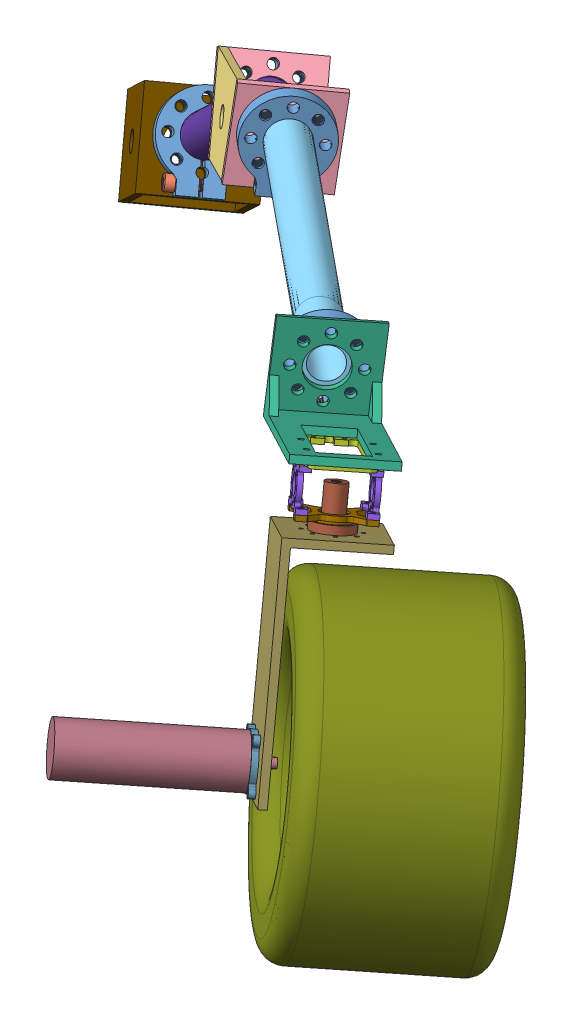
SolidWorks assembly ROVER_ASSM, configuration Default. Lengths in mm.
Overall size (756.93 575.28 702.78).
39 component instances, 18 part files, 23 mates.
Components (placement in the parent):
- Clamping hub 1inch-1: Clamping hub 1inch [Default] at (-73.9561 214.0923 1402.8764) x (0.66198 -0.147614 -0.734841) z (-0.023433 0.975859 -0.217139) size (50.8 9.91 57.17)
  - 545356-1: 545356 [Default] at (-68.793 17.8362 24.1343) size (50.8 9.91 57.17)
  - 91251A542_91251A542-1: 91251A542_91251A542 [Default] at (-81.493 22.5987 -1.2123) x (0 0 1) z (-1 0 0) size (9.53 9.53 32.08)
- Middle_hub_subassem-1: Middle_hub_subassem [Default] at (-169.6755 232.0509 1518.4362) x (-0.717563 -0.408048 -0.564447) z (0.66198 -0.147614 -0.734841) size (96.06 567.55 57.15)
  - center_middle_hub-1: center_middle_hub [Default] at (63.6023 29.7357 53.5654) size (86.73 567.55 4.83)
  - Left_right_middle_hub-1: Left_right_middle_hub [Default] at (26.6634 27.2017 62.7035) x (0.965926 0.258819 0) z (0 0 1) size (4.83 57.15 57.15)
  - Left_right_middle_hub-2: Left_right_middle_hub [Default] at (99.6896 28.4508 62.7035) x (0.965926 -0.258819 0) z (0 0 1) size (4.83 57.15 57.15)
- 1OD tubing bent-2: 1OD tubing bent [Default<As Machined>] at (-21.8827 243.4944 1537.4966) x (-0.749155 -0.160962 -0.642541) z (0.66198 -0.147614 -0.734841) size (269.75 179.7 25.4)
- Clamping hub 1inch-6: Clamping hub 1inch [Default] at (117.7515 256.9533 1566.1024) x (0.661092 -0.120859 -0.740507) z (-0.041537 0.979533 -0.196952) size (50.8 9.91 57.17)
  - 545356-1: 545356 [Default] at (-68.793 17.8362 24.1343) size (50.8 9.91 57.17)
  - 91251A542_91251A542-1: 91251A542_91251A542 [Default] at (-81.493 22.5987 -1.2123) x (0 0 1) z (-1 0 0) size (9.53 9.53 32.08)
- Front_wheel_SUBASSEM-1: Front_wheel_SUBASSEM [Default] at (124.6017 279.882 1760.4193) x (-0.712877 -0.408999 -0.569672) z (0.661092 -0.120859 -0.740507) size (203.2 315.88 229.31)
  - Servo_base_front-1: Servo_base_front [Default] at (66.9376 47.4067 44.7676) size (127 55.2 57.15)
  - servo_mount-1: servo_mount [Default] at (63.4948 44.2317 73.3426) size (79.25 3.17 42.93)
  - wheel_hold_left_right-1: wheel_hold_left_right [Default] at (47.8121 31.5317 51.8796) x (0 -1 0) z (-1 0 0) size (25.4 6.35 33.02)
  - wheel_hold_left_right-2: wheel_hold_left_right [Default] at (47.8121 31.5317 94.8056) x (0 1 0) z (-1 0 0) size (25.4 6.35 33.02)
  - Bearing_mount_subsubass-1: Bearing_mount_subsubass [Default] at (82.6306 37.2877 87.6325) x (0 0 -1) z (-1 0 0) size (42.93 5.08 33.27)
    - 535182-1: 535182 [Default] at (14.2899 18.456 34.8186) size (42.93 5.08 33.27)
    - .5 x .75 non flanged bearing-1: .5 x .75 non flanged bearing [Default] at (14.2899 19.5736 34.8186) x (0.770155 0 0.637857) z (-0.637857 0 0.770155) size (19.05 3.91 19.05)
  - Mounting_hub_circular_servo-1: Mounting_hub_circular_servo [Default] at (47.8121 8.9765 73.3426) x (-0.707107 0 -0.707107) z (0.707107 0 -0.707107) size (25.39 25.4 25.39)
  - Wheel_extension_sheet-2: Wheel_extension_sheet [Default] at (19.2371 8.9765 101.9176) size (57.15 139.7 57.15)
  - Motor_and_mount_subass-1: Motor_and_mount_subass [Default] at (28.0226 -206.4882 -27.8911) x (0.696282 0.717769 0) z (0 0 1) size (46.7 46.7 115)
    - Motors-1: Motors [Default] at (81.834 51.8135 -31.3435) size (32 32 115)
    - Motor_mount-2: Motor_mount [Default] at (45.268 5.1287 35.3702) x (-0.707107 -0.707107 0) z (-0.707107 0.707107 0) size (33.02 8.74 33.02)
      - 555174-1: 555174 [Default] at (-58.8675 33.2863 7.1552) size (33.02 4.05 33.02)
      - 555174 screw_92005A116-1: 555174 screw_92005A116 [Default] at (-68.0596 28.5563 -2.0369) x (1 0 0) z (0 1 0) size (6 6 8.48)
      - 555174 screw_92005A116-2: 555174 screw_92005A116 [Default] at (-68.0596 28.5563 16.3474) x (0 0 -1) z (0 1 0) size (6 6 8.48)
      - 555174 screw_92005A116-3: 555174 screw_92005A116 [Default] at (-49.6753 28.5563 16.3474) x (-1 0 0) z (0 1 0) size (6 6 8.48)
      - 555174 screw_92005A116-4: 555174 screw_92005A116 [Default] at (-49.6753 28.5563 -2.0369) x (0 0 1) z (0 1 0) size (6 6 8.48)
  - wheel_exa_1-1: wheel_exa_1 [Default] at (47.8121 -111.6735 55.7793) size (203.2 203.2 116.84)
- subassem_rightlink-1: subassem_rightlink [Default] at (-260.8229 137.638 1643.4581) x (-0.63707 -0.627327 -0.447887) z (0.66198 -0.147614 -0.734841) size (312.87 60.57 63.5)
  - tubing1rl-1: tubing1rl [Default<As Machined>] at (32.4558 163.244 220.4128) size (254 25.4 25.4)
  - Clamping hub 1inch-1: Clamping hub 1inch [Default] at (14.6195 139.1097 289.2058) x (0 0 1) z (0 1 0) size (50.8 9.91 57.17)
    - 545356-1: 545356 [Default] at (-68.793 17.8362 24.1343) size (50.8 9.91 57.17)
    - 91251A542_91251A542-1: 91251A542_91251A542 [Default] at (-81.493 22.5987 -1.2123) x (0 0 1) z (-1 0 0) size (9.53 9.53 32.08)
  - Clamping hub 1inch-2: Clamping hub 1inch [Default] at (299.466 139.1097 151.6198) x (0 0 -1) z (0 1 0) size (50.8 9.91 57.17)
    - 545356-1: 545356 [Default] at (-68.793 17.8362 24.1343) size (50.8 9.91 57.17)
    - 91251A542_91251A542-1: 91251A542_91251A542 [Default] at (-81.493 22.5987 -1.2123) x (0 0 1) z (-1 0 0) size (9.53 9.53 32.08)
  - right_block-1: right_block [Default] at (345.1298 163.244 220.4128) x (0 0 1) z (-1 0 0) size (63.5 57.15 63.5)
Mates (geometry in assembly coordinates):
- Concentric1: concentric anti-aligned: cylinder of ? through (329.3554 390.3641 930.5142) axis (0 0 -1) radius 12.7; cylinder of Clamping hub 1inch-1/545356-1 through (329.3554 390.3641 182.4842) axis (0 0 1) radius 12.7
- Coincident1: coincident aligned: plane of ? through (329.3554 390.3641 177.6582) normal (0 0 -1); plane of Middle_hub_subassem-1/Left_right_middle_hub-1
- Coincident3: coincident anti-aligned: plane of Clamping hub 1inch-1/545356-1 through (-140.5591 243.3947 1430.6072) normal (-0.749155 -0.160962 -0.642541); plane of Middle_hub_subassem-1/Left_right_middle_hub-1 through (-153.1896 236.4223 1447.08) normal (0.749155 0.160962 0.642541)
- Concentric3: concentric anti-aligned: cylinder of Clamping hub 1inch-1/545356-1 through (-141.0055 261.9848 1426.4707) axis (-0.749155 -0.160962 -0.642541) radius 3.175; cylinder of Middle_hub_subassem-1/Left_right_middle_hub-1 through (-144.6209 261.208 1423.3698) axis (0.749155 0.160962 0.642541) radius 3.175
- Coincident4: coincident anti-aligned: plane of Clamping hub 1inch-1/545356-1 through (-140.5591 243.3947 1430.6072) normal (-0.749155 -0.160962 -0.642541); plane of Middle_hub_subassem-1/Left_right_middle_hub-1 through (-153.1896 236.4223 1447.08) normal (0.749155 0.160962 0.642541)
- Concentric4: concentric anti-aligned: cylinder of Clamping hub 1inch-1/545356-1 through (-141.0055 261.9848 1426.4707) axis (-0.749155 -0.160962 -0.642541) radius 3.175; cylinder of Middle_hub_subassem-1/Left_right_middle_hub-1 through (-144.6209 261.208 1423.3698) axis (0.749155 0.160962 0.642541) radius 3.175
- Concentric5: concentric anti-aligned: cylinder of Clamping hub 1inch-1/545356-1 through (-127.9484 240.5826 1416.6084) axis (-0.749155 -0.160962 -0.642541) radius 3.175; cylinder of Middle_hub_subassem-1/Left_right_middle_hub-1 through (-131.5638 239.8058 1413.5075) axis (0.749155 0.160962 0.642541) radius 3.175
- Parallel13: parallel aligned: line of Middle_hub_subassem-1/Left_right_middle_hub-1 through (-141.1543 268.1815 1425.0918) axis (0.023433 -0.975859 0.217139); line of 1OD tubing bent-2 through (-144.4721 255.0113 1424.7486) axis (0.023433 -0.975859 0.217139)
- Concentric14: concentric aligned: cylinder of Clamping hub 1inch-1/545356-1 through (-140.5591 243.3947 1430.6072) axis (0.749155 0.160962 0.642541) radius 12.7; cylinder of 1OD tubing bent-2 through (-144.1745 242.6179 1427.5063) axis (0.749155 0.160962 0.642541) radius 12.7
- Coincident15: coincident aligned: plane of Middle_hub_subassem-1/Left_right_middle_hub-1 through (-156.805 235.6455 1443.9791) normal (-0.749155 -0.160962 -0.642541); plane of 1OD tubing bent-2 through (-144.1745 242.6179 1427.5063) normal (-0.749155 -0.160962 -0.642541)
- Concentric22: concentric aligned: cylinder of 1OD tubing bent-2 through (19.8514 277.8601 1568.1893) axis (0.749155 0.160962 0.642541) radius 12.7; cylinder of Clamping hub 1inch-6/545356-1 through (50.7727 284.5038 1594.7102) axis (0.749155 0.160962 0.642541) radius 12.7
- Coincident36: coincident aligned: plane of 1OD tubing bent-2 through (57.9084 286.037 1600.8304) normal (0.749155 0.160962 0.642541); plane of Clamping hub 1inch-6/545356-1 through (57.9084 286.037 1600.8304) normal (0.749155 0.160962 0.642541)
- Concentric25: concentric aligned: cylinder of Clamping hub 1inch-6/545356-1 through (103.4177 293.5013 1550.1751) axis (-0.168495 -0.258819 -0.951116) radius 3.175; cylinder of ? through (126.4216 328.8368 1680.0272) axis (-0.168495 -0.258819 -0.951116) radius 3.175
- Coincident38: coincident anti-aligned: plane of Clamping hub 1inch-6/545356-1; plane of ? through (135.453 246.8975 1567.1963) normal (-0.168495 -0.258819 -0.951116)
- Concentric26: concentric aligned: cylinder of Clamping hub 1inch-6/545356-1 through (123.0357 275.1004 1551.7069) axis (-0.168495 -0.258819 -0.951116) radius 3.175; cylinder of ? through (146.0396 310.4359 1681.559) axis (-0.168495 -0.258819 -0.951116) radius 3.175
- Coincident39: coincident anti-aligned: plane of ? through (136.0483 252.8081 1570.5564) normal (-0.045148 0.965926 -0.254851); plane of ? through (132.7113 273.5609 1649.8042) normal (0.045148 -0.965926 0.254851)
- Parallel14: parallel anti-aligned: line of ? through (112.572 281.8652 1684.8465) axis (0.984668 0 -0.174439); line of ? through (152.8215 282.3826 1667.219) axis (-0.984668 0 0.174439)
- Coincident40: coincident anti-aligned: plane of Clamping hub 1inch-6/545356-1 through (57.9084 286.037 1600.8304) normal (0.749155 0.160962 0.642541); plane of Front_wheel_SUBASSEM-1/Servo_base_front-1 through (78.1179 251.4833 1585.9236) normal (-0.749155 -0.160962 -0.642541)
- Concentric27: concentric aligned: cylinder of Clamping hub 1inch-6/545356-1 through (49.9815 303.1639 1590.9582) axis (-0.749155 -0.160962 -0.642541) radius 3.175; cylinder of Front_wheel_SUBASSEM-1/Servo_base_front-1 through (149.0188 324.4429 1675.9013) axis (-0.749155 -0.160962 -0.642541) radius 3.175
- Concentric28: concentric aligned: cylinder of Clamping hub 1inch-6/545356-1 through (38.179 286.8062 1608.8168) axis (-0.749155 -0.160962 -0.642541) radius 3.175; cylinder of Front_wheel_SUBASSEM-1/Servo_base_front-1 through (137.2163 308.0851 1693.7599) axis (-0.749155 -0.160962 -0.642541) radius 3.175
- Concentric29: concentric anti-aligned: cylinder of Middle_hub_subassem-1/Left_right_middle_hub-2 through (-207.5732 224.1305 1374.1074) axis (0.63707 0.627327 0.447887) radius 3.175; cylinder of subassem_rightlink-1/Clamping hub 1inch-1/545356-1 through (-213.6413 218.1552 1369.8413) axis (-0.63707 -0.627327 -0.447887) radius 3.175
- Concentric30: concentric anti-aligned: cylinder of Middle_hub_subassem-1/Left_right_middle_hub-2 through (-187.4402 206.7521 1369.8112) axis (0.63707 0.627327 0.447887) radius 3.175; cylinder of subassem_rightlink-1/Clamping hub 1inch-1/545356-1 through (-193.5083 200.7768 1365.5451) axis (-0.63707 -0.627327 -0.447887) radius 3.175
- Coincident41: coincident anti-aligned: plane of Middle_hub_subassem-1/Left_right_middle_hub-2 through (-208.9355 204.722 1403.2294) normal (-0.63707 -0.627327 -0.447887); plane of subassem_rightlink-1/Clamping hub 1inch-1/545356-1 through (-200.0509 209.5642 1383.8099) normal (0.63707 0.627327 0.447887)
